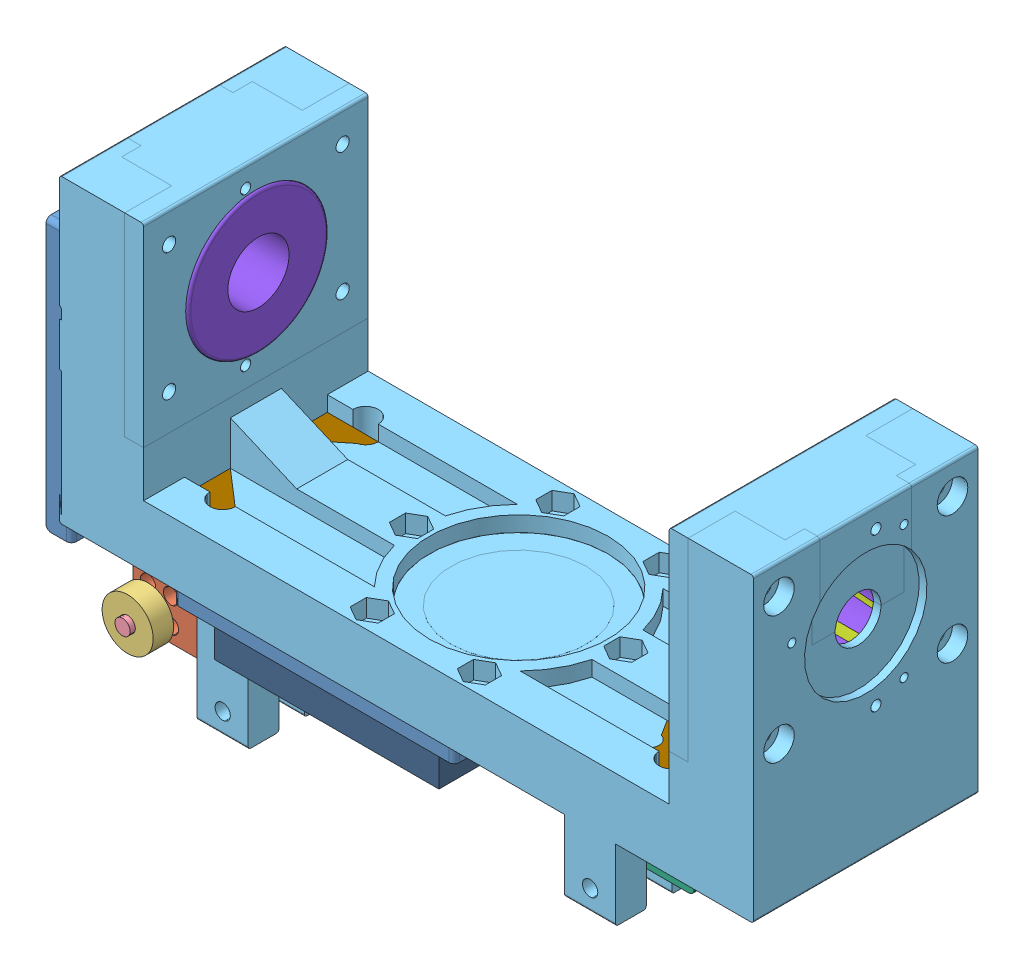
SolidWorks assembly link2, configuration 默认. Lengths in mm.
Overall size (138.77 80 58.66).
22 component instances, 10 part files, 5 mates.
Components (placement in the parent):
- Shoulder_Joint_Fix_L_ASS-1: Shoulder_Joint_Fix_L_ASS [默认] at (-8.5883 9.1785 14) size (80 71.53 44) (hidden)
  - Shoulder_Joint_Fix_L-1: Shoulder_Joint_Fix_L [默认] at (-2.8963 -28.6407 70) size (80 53 44)
  - Shoulder_Joint_Fix_BC_L-2: Shoulder_Joint_Fix_BC_L [默认] at (-25.8963 -28.6407 70) x (0 0 1) z (1 0 0) size (28 15 16)
  - Shoulder_Joint_Fix_Pulley_3_10_4-1: Shoulder_Joint_Fix_Pulley_3_10_4 [默认] at (-30.8963 -40.6407 88) x (-0.923728 -0.383049 0) z (0.383049 -0.923728 0) size (10 4 10)
  - Shoulder_Joint_Fix_Pulley_3_10_4-2: Shoulder_Joint_Fix_Pulley_3_10_4 [默认] at (-30.8963 -40.6407 56) x (-0.923728 -0.383049 0) z (0.383049 -0.923728 0) size (10 4 10)
  - Shoulder_Joint_Fix_Axis_3_38-1: Shoulder_Joint_Fix_Axis_3_38 [默认] at (-30.8963 -40.6407 70) x (0 0 1) z (0.923728 0.383049 0) size (38 3 3)
- Shoulder_Joint_Fix_R_ASS-1: Shoulder_Joint_Fix_R_ASS [默认] at (43.9453 12.2859 154) x (-1 0 0) z (0 0 -1) size (138.77 80 58.66)
  - Shoulder_Joint_Fix_R_mill_V0_3_160824-1: Shoulder_Joint_Fix_R_mill_V0_3_160824 [默认] at (7.3038 -26.248 70) size (138.77 80 58.66)
  - Shoulder_Joint_Fix_BC_R-1: Shoulder_Joint_Fix_BC_R [默认] at (-15.6962 -26.248 69.8499) x (0 0 1) z (1 0 0) size (28 12 16) (hidden)
  - Shoulder_Joint_Fix_Pulley_3_10_4-1: Shoulder_Joint_Fix_Pulley_3_10_4 [默认] at (-16.1962 -34.248 85) x (1 0 0) z (0 -1 0) size (10 4 10) (hidden)
  - Shoulder_Joint_Fix_Pulley_3_10_4-2: Shoulder_Joint_Fix_Pulley_3_10_4 [默认] at (-16.1962 -34.248 55) x (-0.923728 -0.383049 0) z (0.383049 -0.923728 0) size (10 4 10) (hidden)
  - shoulder_elbow_wireguide-1: shoulder_elbow_wireguide [Default] at (91.5212 -15.1598 75.5) x (0 0 -1) z (-1 0 0) size (36 17 16) (hidden)
    - Shoulder_Joint_Fix_BC_L-1: Shoulder_Joint_Fix_BC_L [默认] at (5.7098 11.3402 26.2174) size (28 15 16)
    - Shoulder_Joint_Fix_Pulley_3_10_4-1: Shoulder_Joint_Fix_Pulley_3_10_4 [默认] at (19.7098 23.3402 25.7174) x (0 -1 0) z (0 0 1) size (10 4 10)
    - Shoulder_Joint_Fix_Pulley_3_10_4-2: Shoulder_Joint_Fix_Pulley_3_10_4 [默认] at (-12.2902 23.3402 25.7174) x (0 -1 0) z (0 0 1) size (10 4 10)
  - GunzhenZhoucheng-1: GunzhenZhoucheng [默认] at (-26.1962 10.752 70) x (0 -0.924225 -0.381849) z (-1 0 0) size (27.5 27.5 15.2)
  - GunzhenZhoucheng-2: GunzhenZhoucheng [默认] at (89.3038 10.752 70) x (0 0 1) z (-1 0 0) size (27.5 27.5 15.2) (hidden)
  - shoulder_elbow_joint_RAX712-1: shoulder_elbow_joint_RAX712 [默认] at (-26.1962 10.752 70) x (0 -0.924225 -0.381849) z (-1 0 0) size (27.5 27.5 14.2)
  - shoulder_elbow_joint_RAX712-2: shoulder_elbow_joint_RAX712 [默认] at (75.8038 10.752 70) x (0 0.924225 0.381849) z (1 0 0) size (27.5 27.5 14.2)
  - Shoulder_Joint_SUP_V1-1: Shoulder_Joint_SUP_V1 [Default] at (-20.1962 -20.248 70) x (-1 0 0) z (0 -1 0) size (24.5 28 12)
  - Shoulder_Joint_SUP_V1-2: Shoulder_Joint_SUP_V1 [Default] at (69.8038 -20.248 70) x (1 0 0) z (0 -1 0) size (24.5 28 12)
- Shoulder_Joint_AX_basement_square-1: Shoulder_Joint_AX_basement_square [默认] at (3.5154 -19.4621 84) x (1 0 0) z (0 0 -1) size (44 5.5 44) (hidden)
Mates (geometry in assembly coordinates):
- 距离9: distance = 2.5 mm anti-aligned: plane of Shoulder_Joint_Fix_L_ASS-1/Shoulder_Joint_Fix_L-1 through (-11.4846 -16.4621 84) normal (0 1 0); plane of Shoulder_Joint_Fix_R_ASS-1/Shoulder_Joint_Fix_R_mill_V0_3_160824-1 through (36.6415 -13.9621 84) normal (0 -1 0)
- 重合7: coincident aligned: plane of Shoulder_Joint_Fix_L_ASS-1/Shoulder_Joint_Fix_L-1 through (-51.4846 -16.4621 62) normal (0 0 -1); plane of Shoulder_Joint_Fix_R_ASS-1/Shoulder_Joint_Fix_R_mill_V0_3_160824-1 through (79.1415 1.0379 62) normal (0 0 -1)
- 同心10: concentric anti-aligned: cylinder of Shoulder_Joint_Fix_L_ASS-1/Shoulder_Joint_Fix_L-1 through (3.5154 -16.4621 84) axis (0 -1 0) radius 13.75; cylinder of Shoulder_Joint_AX_basement_square-1 through (3.5154 -26.4621 84) axis (0 1 0) radius 9
- 重合14: coincident anti-aligned: plane of Shoulder_Joint_Fix_L_ASS-1/Shoulder_Joint_Fix_L-1 through (-11.4846 -19.4621 84) normal (0 -1 0); plane of Shoulder_Joint_AX_basement_square-1 through (3.5154 -19.4621 84) normal (0 1 0)
- 重合15: coincident aligned: plane of Shoulder_Joint_Fix_L_ASS-1/Shoulder_Joint_Fix_L-1 through (-51.4846 -16.4621 106) normal (0 0 1); plane of Shoulder_Joint_AX_basement_square-1 through (-18.4846 -24.9621 106) normal (0 0 1)
